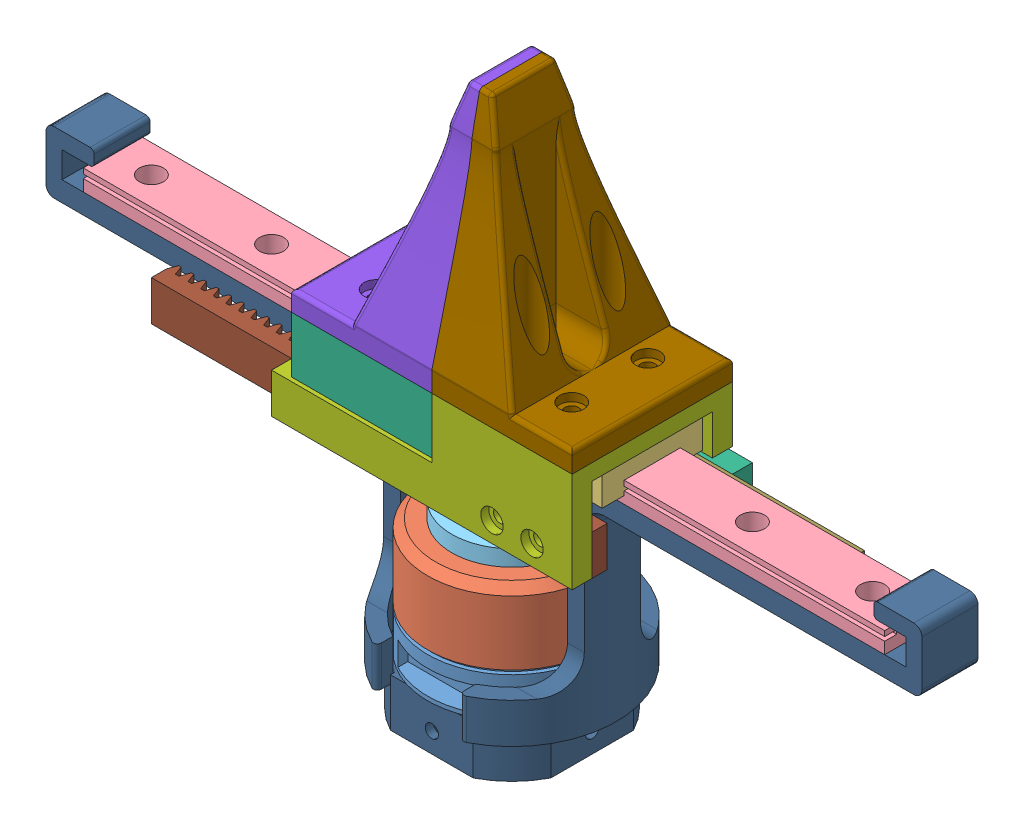
SolidWorks assembly MyGripper, configuration 默认. Lengths in mm.
Overall size (218.6 138.06 52.44).
17 component instances, 14 part files, 36 mates.
Components (placement in the parent):
- 3510-1: 3510 [默认] at origin size (52.44 31.5 52.44)
  - 3510定子-1: 3510定子 [默认] at origin size (42 27.5 42)
  - 3510转子-1: 3510转子 [默认] at (0 29 0) x (-0.956343 0 0.292248) z (0.292248 0 0.956343) size (42 19 42)
- MGW9滑轨模组-2: MGW9滑轨模组 [默认] at (0 53 7) size (200 9 25) (flexible)
  - MGW9C滑块-1: MGW9C滑块 [默认] at (-35 1.9 5.5) size (31.2 7.1 25)
  - MGW9导轨-1: MGW9导轨 [默认] at (-100 0 0) size (200 5.2 14)
  - MGW9C滑块-2: MGW9C滑块 [默认] at (35 1.9 -19.5) x (-1 0 0) z (0 0 -1) size (31.2 7.1 25)
- 转子齿轮连接件-1: 转子齿轮连接件 [默认] at (0 29 0) x (0.956343 0 -0.292248) z (0.292248 0 0.956343) size (30 22 30)
- 滑块手指连接件-1: 滑块手指连接件 [默认] at (-35 62 20) size (75 25 40)
- 滑块手指连接件2-1: 滑块手指连接件2 [默认] at (35 62 -20) x (-1 0 0) z (0 0 -1) size (75 25 40)
- 手指-1: 手指 [默认] at (0 66 -20) x (-1 0 0) z (0 0 -1) size (35 60.06 42.71)
- 镜向手指-2: 镜向手指 [默认] at (0 66 -20) size (35 60.06 42.71)
- 夹爪外壳-1: 夹爪外壳 [默认] at (0 -2 0) size (218.6 75.5 49.28)
- 齿条-1: 齿条 [默认] at (35 51 15) x (-1 0 0) z (0 0 1) size (110 10 6)
- 齿条2-1: 齿条2 [默认] at (-35 51 -15) x (1 0 0) z (0 0 -1) size (108 10 6)
- spur gear_gb-1: spur gear_gb [GB - Spur gear 1M 20T 20PA 10FW ---S20B16H18L10.0N] at (0 41.0001 0) x (0 1 0) z (0.158015 0 0.987437) size (18 21.8 21.8)
- 外壳内挡块-1: 外壳内挡块 [默认] at (0 -2 0) x (-1 0 0) z (0 0 1) size (28 9.5 28)
Mates (geometry in assembly coordinates):
- 同心1: concentric anti-aligned: circle of 3510-1/3510转子-1; circle of 转子齿轮连接件-1
- 重合1: coincident anti-aligned: plane of 3510-1/3510转子-1 through (0 29 0) normal (0 1 0); plane of 转子齿轮连接件-1 through (0 29 0) normal (0 -1 0)
- 同心2: concentric aligned: cylinder of 3510-1/3510转子-1 through (-7.7947 12 -1.8006) axis (0 1 0) radius 1.5; cylinder of 转子齿轮连接件-1 through (-7.7947 28 -1.8006) axis (0 1 0) radius 1.6
- 同心4: concentric anti-aligned: cylinder of MGW9滑轨模组-2/MGW9导轨-1 through (0 27.2 0) axis (0 1 0) radius 1.75; cylinder of 转子齿轮连接件-1 through (0 33 0) axis (0 -1 0) radius 15
- 重合8: coincident anti-aligned: plane of 3510-1/3510定子-1 through (0 0 0) normal (0 -1 0)
- 同心5: concentric anti-aligned: circle of 3510-1/3510定子-1
- 平行4: parallel aligned: plane of 3510-1/3510定子-1 through (0 0 16) normal (0 0 1)
- 平行5: parallel aligned: plane of 3510-1/3510定子-1 through (0 0 16) normal (0 0 1); plane of MGW9滑轨模组-2/MGW9导轨-1 through (-100 58.2 7) normal (0 0 1)
- 同心6: concentric aligned: cylinder of MGW9滑轨模组-2/MGW9C滑块-1 through (-14.4 60 9.5) axis (0 1 0) radius 1.5; cylinder of 滑块手指连接件-1 through (-14.4 60 9.5) axis (0 1 0) radius 1.6
- 同心7: concentric aligned: cylinder of MGW9滑轨模组-2/MGW9C滑块-1 through (-14.4 60 -9.5) axis (0 1 0) radius 1.5; cylinder of 滑块手指连接件-1 through (-14.4 60 -9.5) axis (0 1 0) radius 1.6
- 重合18: coincident anti-aligned: plane of MGW9滑轨模组-2/MGW9C滑块-1 through (-35 62 12.5) normal (0 1 0); plane of 滑块手指连接件-1 through (-35 62 20) normal (0 -1 0)
- 同心9: concentric aligned: cylinder of 滑块手指连接件2-1 through (24.5083 60 9.5) axis (0 1 0) radius 1.6; cylinder of MGW9滑轨模组-3/MGW9C滑块-1 through (25.65 66 10.5) axis (0 1 0) radius 1.5
- 重合23: coincident anti-aligned: plane of 滑块手指连接件-1 through (-35 66 20) normal (0 1 0); plane of 手指-1 through (0 66 -20) normal (0 -1 0)
- 重合27: coincident anti-aligned: plane of 3510-1/3510定子-1 through (0 0 0) normal (0 -1 0); plane of 夹爪外壳-1 through (0 0 0) normal (0 1 0)
- 同心11: concentric aligned: cylinder of 3510-1/3510定子-1 through (-12.7279 4 12.7279) axis (0 -1 0) radius 1.5; cylinder of 夹爪外壳-1 through (-12.7279 0 12.7279) axis (0 -1 0) radius 1.6
- 同心12: concentric aligned: cylinder of 3510-1/3510定子-1 through (12.7279 4 12.7279) axis (0 -1 0) radius 1.5; cylinder of 夹爪外壳-1 through (12.7279 0 12.7279) axis (0 -1 0) radius 1.6
- 宽度4: width aligned: plane of 滑块手指连接件-1 through (-35 66 -20) normal (0 0 -1); plane of 滑块手指连接件-1 through (-35 66 20) normal (0 0 1); plane of 手指-1 through (0 71 -20) normal (0 0 -1); plane of 手指-1 through (0 71 20) normal (0 0 1)
- 重合36: coincident anti-aligned: plane of MGW9滑轨模组-3/MGW9导轨-1 through (100 56 -9) normal (0 -1 0); plane of 夹爪外壳-1 through (0 53 0) normal (0 1 0)
- 同心15: concentric anti-aligned: cylinder of 滑块手指连接件2-1 through (25 46 18) axis (0 0 1) radius 2.8; cylinder of 齿条-1 through (25 46 21.25) axis (0 0 -1) radius 1.6
- 同心16: concentric anti-aligned: cylinder of 滑块手指连接件2-1 through (15 46 18) axis (0 0 1) radius 2.8; cylinder of 齿条-1 through (15 46 21.25) axis (0 0 -1) radius 1.6
- 重合38: coincident anti-aligned: plane of 滑块手指连接件2-1 through (35 41 15) normal (0 0 -1); plane of 齿条-1 through (35 41 15) normal (0 0 1)
- 同心17: concentric anti-aligned: cylinder of 滑块手指连接件-1 through (-25 46 -5) axis (0 0 -1) radius 1.6; cylinder of 齿条2-1 through (-25 46 -21.25) axis (0 0 1) radius 1.6
- 同心18: concentric anti-aligned: cylinder of 滑块手指连接件-1 through (-15 46 -5) axis (0 0 -1) radius 1.6; cylinder of 齿条2-1 through (-15 46 -21.25) axis (0 0 1) radius 1.6
- 重合39: coincident anti-aligned: plane of 滑块手指连接件-1 through (-35 41 -15) normal (0 0 1); plane of 齿条2-1 through (-35 41 -15) normal (0 0 -1)
- 重合40: coincident anti-aligned: plane of MGW9滑轨模组-2/MGW9导轨-1 through (-100 53 7) normal (0 -1 0); plane of 夹爪外壳-1 through (0 53 0) normal (0 1 0)
- 同心19: concentric anti-aligned: cylinder of 滑块手指连接件-1 through (-24.4 60 9.5) axis (0 1 0) radius 1.6; cylinder of 手指-1 through (-24.4 111 9.5) axis (0 -1 0) radius 1.75
- 宽度5: width anti-aligned: plane of MGW9滑轨模组-2/MGW9导轨-1 through (-100 58.2 7) normal (-1 0 0); plane of 手指-1 through (0 71 -20) normal (1 0 0); plane of 手指-1 through (-35 71 -20) normal (-1 0 0)
- 同心20: concentric aligned: cylinder of 转子齿轮连接件-1 through (0 51 0) axis (0 -1 0) radius 5; cylinder of spur gear_gb-1 through (0 59.0001 0) axis (0 -1 0) radius 5
- 重合41: coincident anti-aligned: plane of 转子齿轮连接件-1 through (0 33 0) normal (0 1 0); plane of spur gear_gb-1 through (0 33 0) normal (0 -1 0)
- 同心21: concentric anti-aligned: cylinder of 滑块手指连接件2-1 through (14.4 60 9.5) axis (0 1 0) radius 1.6; cylinder of 镜向手指-2 through (14.4 111 9.5) axis (0 -1 0) radius 1.75
- 同心22: concentric anti-aligned: cylinder of 滑块手指连接件2-1 through (24.4 60 -9.5) axis (0 1 0) radius 1.6; cylinder of 镜向手指-2 through (24.4 111 -9.5) axis (0 -1 0) radius 1.75
- 重合42: coincident anti-aligned: plane of 滑块手指连接件2-1 through (35 66 -20) normal (0 1 0); plane of 镜向手指-2 through (0 66 -20) normal (0 -1 0)
- RackPinionMate1: rack pinion = 17.498 mm: line of 齿条2-1 through (6.1992 41 -9.0004) axis (-1 0 0); circle of spur gear_gb-1
- 重合43: coincident anti-aligned: plane of 夹爪外壳-1 through (0 -2 0) normal (0 -1 0); plane of 外壳内挡块-1 through (0 -2 0) normal (0 1 0)
- 同心24: concentric aligned: cylinder of 3510-1/3510定子-1 through (0 -1.5 0) axis (0 1 0) radius 9; cylinder of 外壳内挡块-1 through (0 -11.5 0) axis (0 1 0) radius 7.5
- 平行6: parallel anti-aligned: plane of 夹爪外壳-1 through (-9.0139 -12 15) normal (0 0 -1); plane of 外壳内挡块-1 through (-8 -11.5 14) normal (0 0 1)
